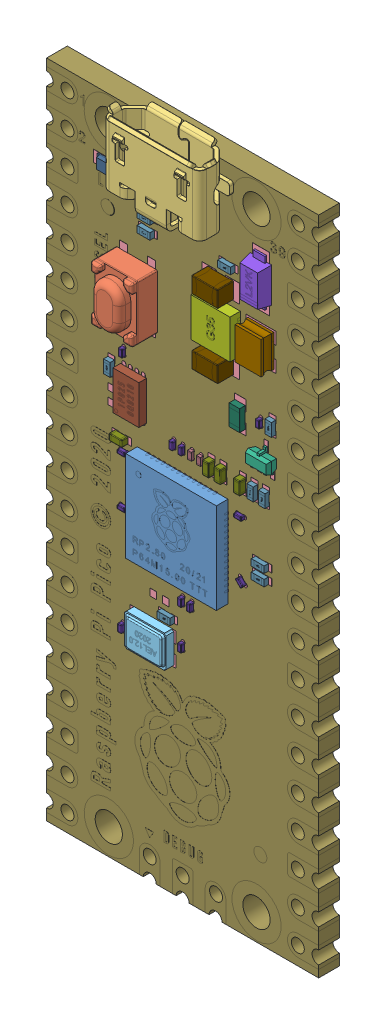
SolidWorks assembly RaspBerryPi Pico, configuration Default. Lengths in mm.
Overall size (21 52.11 4.3).
47 component instances, 18 part files, 0 mates.
Components (placement in the parent):
- RaspBerryPi Pico.iges-1: RaspBerryPi Pico.iges [Default] at origin size (21 52.11 4.3)
  - RP2040 v6.iges-1: RP2040 v6.iges [Default] at (0 -22.49 1.6) size (7 7 0.91)
  - BOOTSEL v3.iges-1: BOOTSEL v3.iges [Default] at (-3.55 -9.9 1.6) size (3.24 4.29 2.5)
  - USB microB v9.iges-1: USB microB v9.iges [Default] at (0 0 1.6) size (8.03 5.81 2.94)
  - RaspberryPi Pico_Solder v8.iges-1: RaspberryPi Pico_Solder v8.iges [Default] at origin size (14.09 32.5 0.01)
  - Crystal unit v2.iges-1: Crystal unit v2.iges [Default] at (-2.275 -34.55 1.6) size (3.2 2.5 0.82)
  - Transistor v1.iges-1: Transistor v1.iges [Default] at (6.445 -18.25 1.6) size (1.8 1.6 0.8)
  - RT6150B-33GQW v1.iges-1: RT6150B-33GQW v1.iges [Default] at (2.95 -10.95 1.6) size (3 3 0.81)
  - MBR120VLSFT1G v1.iges-1: MBR120VLSFT1G v1.iges [Default] at (6.05 -6.5 1.6) size (1.65 3.6 0.95)
  - L2520 v1.iges-1: L2520 v1.iges [Default] at (6.05 -10.8 1.6) size (2 2.5 1)
  - LED1608_04 v1.iges-1: LED1608_04 v1.iges [Default] at (-5.7 -4.72 1.6) x (0 1 0) z (0 0 1) size (0.8 1.6 0.4)
  - W25Q16JV_UX v3.iges-1: W25Q16JV_UX v3.iges [Default] at (-3.78 -19.05 1.6) size (2 3 0.6)
  - RaspBerryPi Pico_CircuitBoard_logo v15.iges-1: RaspBerryPi Pico_CircuitBoard_logo v15.iges [Default] at origin size (21 51 1.61)
  - Resistor.iges-1: Resistor.iges [Default] at origin size (12.95 26.49 0.45)
    - R0603 v2.iges-1: R0603 v2.iges [Default] at (0.75 -20.85 1.6) size (0.3 0.6 0.23)
    - R0603 v2.iges-2: R0603 v2.iges [Default] at (1.45 -20.85 1.6) size (0.3 0.6 0.23)
    - R1005 v1.iges-1: R1005 v1.iges [Default] at (5.55 -20.86 1.6) size (0.5 1 0.36)
    - R1005 v1.iges-2: R1005 v1.iges [Default] at (6.45 -20.86 1.6) size (0.5 1 0.36)
    - R1005 v1.iges-3: R1005 v1.iges [Default] at (6.14 -25.47 1.6) x (0 -1 0) z (0 0 1) size (0.5 1 0.36)
    - R1005 v1.iges-4: R1005 v1.iges [Default] at (6.14 -26.37 1.6) x (0 -1 0) z (0 0 1) size (0.5 1 0.36)
    - R1005 v1.iges-5: R1005 v1.iges [Default] at (3.54 -6.805 1.6) x (0 -1 0) z (0 0 1) size (0.5 1 0.36)
    - R1005 v1.iges-6: R1005 v1.iges [Default] at (-2.68 -7.605 1.6) x (0 -1 0) z (0 0 1) size (0.5 1 0.36)
    - R1005 v1.iges-7: R1005 v1.iges [Default] at (-2.68 -6.605 1.6) x (0 -1 0) z (0 0 1) size (0.5 1 0.36)
    - R1005 v1.iges-8: R1005 v1.iges [Default] at (-5.5 -18.06 1.6) size (0.5 1 0.36)
    - R1005 v1.iges-9: R1005 v1.iges [Default] at (6.95 -15.85 1.6) size (0.5 1 0.36)
    - R1005 v1.iges-10: R1005 v1.iges [Default] at (-2.68 -6.605 1.6) x (0 -1 0) z (0 0 1) size (0.5 1 0.36)
    - R1005 v1.iges-11: R1005 v1.iges [Default] at (-1.125 -32.6 1.6) x (0 -1 0) z (0 0 1) size (0.5 1 0.36)
    - R1608 v1.iges-1: R1608 v1.iges [Default] at (4.445 -16.35 1.6) size (0.8 1.6 0.45)
  - Capacitor.iges-1: Capacitor.iges [Default] at origin size (11.41 27.73 1.26)
    - C1005 v2.iges-1: C1005 v2.iges [Default] at (2.25 -20.86 1.6) size (0.53 1.01 0.51)
    - C1005 v2.iges-2: C1005 v2.iges [Default] at (4.65 -20.86 1.6) size (0.53 1.01 0.51)
    - C1005 v2.iges-3: C1005 v2.iges [Default] at (3.15 -20.86 1.6) size (0.53 1.01 0.51)
    - C1005 v2.iges-4: C1005 v2.iges [Default] at (-4.7 -22.42 1.6) x (0 -1 0) z (0 0 1) size (0.53 1.01 0.51)
    - C0603 v2.iges-1: C0603 v2.iges [Default] at (0.05 -20.85 1.6) size (0.32 0.6 0.31)
    - C0603 v2.iges-2: C0603 v2.iges [Default] at (4.51 -23.06 1.6) x (0 -1 0) z (0 0 1) size (0.32 0.6 0.31)
    - C0603 v2.iges-3: C0603 v2.iges [Default] at (0.73 -30.99 1.6) size (0.32 0.6 0.31)
    - C0603 v2.iges-4: C0603 v2.iges [Default] at (-4.53 -16.59 1.6) size (0.32 0.6 0.31)
    - C0603 v2.iges-5: C0603 v2.iges [Default] at (0.03 -34.04 1.6) size (0.32 0.6 0.31)
    - C0603 v2.iges-6: C0603 v2.iges [Default] at (-4.48 -26.98 1.6) x (0 -1 0) z (0 0 1) size (0.32 0.6 0.31)
    - C0603 v2.iges-7: C0603 v2.iges [Default] at (-4.59 -35.04 1.6) size (0.32 0.6 0.31)
    - C0603 v2.iges-8: C0603 v2.iges [Default] at (-0.65 -20.85 1.6) size (0.32 0.6 0.31)
    - C0603 v2.iges-9: C0603 v2.iges [Default] at (-4.48 -23.27 1.6) x (0 -1 0) z (0 0 1) size (0.32 0.6 0.31)
    - C0603 v2.iges-10: C0603 v2.iges [Default] at (0.03 -30.99 1.6) size (0.32 0.6 0.31)
    - C0603 v2.iges-11: C0603 v2.iges [Default] at (4.6484 -27.3787 1.6) x (0.707107 0.707107 0) z (0 0 1) size (0.32 0.6 0.31)
    - C0603 v2.iges-12: C0603 v2.iges [Default] at (6.05 -16.05 1.6) size (0.32 0.6 0.31)
    - C2012 v2.iges-1: C2012 v2.iges [Default] at (2.925 -13.33 1.6) x (0 -1 0) z (0 0 1) size (1.39 2.01 1.26)
    - C2012 v2.iges-2: C2012 v2.iges [Default] at (2.925 -8.305 1.6) x (0 -1 0) z (0 0 1) size (1.39 2.01 1.26)
